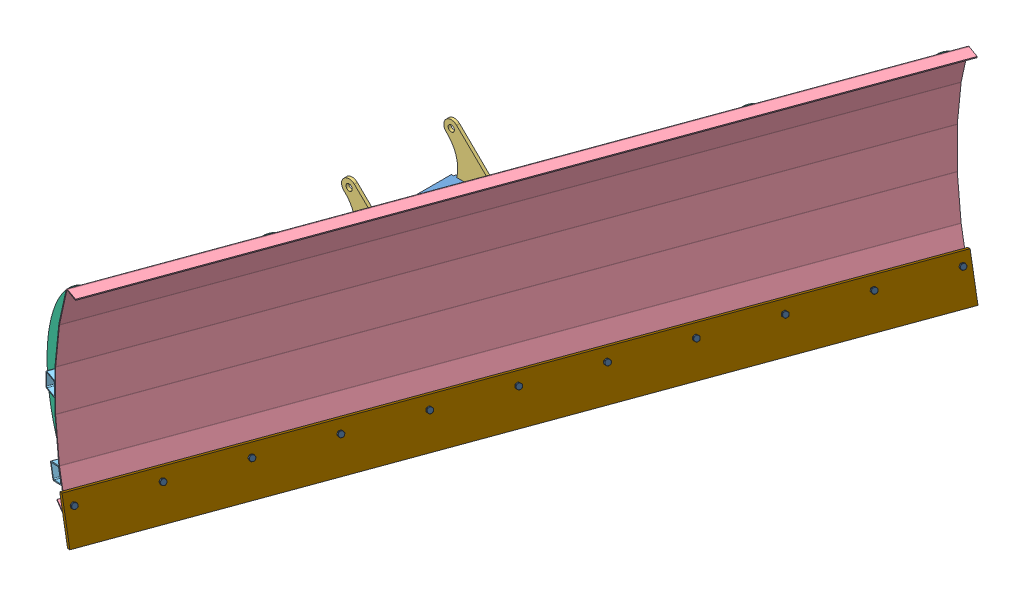
SolidWorks assembly ТП.016.11.00 - Отвал поворотный, configuration 00. Lengths in mm.
Overall size (742.58 437.97 1419.72).
58 component instances, 12 part files, 11 mates.
Components (placement in the parent):
- ТП.016.11.01.00 - Навеска поворотная-1: ТП.016.11.01.00 - Навеска поворотная [00] at origin size (254.02 180 209.34)
  - ТП.016.11.01.01.00 - Цапфа навески нижняя-1: ТП.016.11.01.01.00 - Цапфа навески нижняя [00] at origin size (200 19 209.34)
    - ТП.016.11.01.01.01 - Цапфа навески (Ст3 S-4мм)-1: ТП.016.11.01.01.01 - Цапфа навески (Ст3 S-4мм) [--] at origin size (200 4 209.34)
    - ТП.016.11.01.01.02 - Усилитель цапфы-1: ТП.016.11.01.01.02 - Усилитель цапфы [--] at (0 4 0) size (140.53 15 187.34)
  - ТП.016.11.01.02 - Кронштейн навески (Ст3 S-6мм)-1: ТП.016.11.01.02 - Кронштейн навески (Ст3 S-6мм) [--] at (-42.4802 0.2 98.6677) x (-1 0 0) z (0 0 1) size (156.54 180 6)
  - ТП.016.11.01.01.01 - Цапфа навески (Ст3 S-4мм)-1: ТП.016.11.01.01.01 - Цапфа навески (Ст3 S-4мм) [--] at (0 19.4 0) size (200 4 209.34)
  - ТП.016.11.01.02 - Кронштейн навески (Ст3 S-6мм)-2: ТП.016.11.01.02 - Кронштейн навески (Ст3 S-6мм) [--] at (-42.4802 0.2 -104.6677) x (-1 0 0) z (0 0 1) size (156.54 180 6)
- ТП.016.11.02.00 - Отвал в сборе-1: ТП.016.11.02.00 - Отвал в сборе [00] at (96.0852 49.6474 34.9722) x (0.939693 0 0.34202) z (-0.34202 0 0.939693) size (277.03 437.97 1410)
  - ТП.016.11.02.01 - Полотно отвала (Ст3 S-2мм)-1: ТП.016.11.02.01 - Полотно отвала (Ст3 S-2мм) [--] at origin size (68.17 399.04 1400)
  - ТП.016.11.02.02 - Продольная труба-1: ТП.016.11.02.02 - Продольная труба [--] at origin size (30 30 1400)
  - ТП.016.11.02.02 - Продольная труба-2: ТП.016.11.02.02 - Продольная труба [--] at (-7.8024 -145.4172 0) x (-0.951057 -0.309017 0) z (0 0 1) size (30 30 1400)
  - ТП.016.11.02.03 - Ребро жесткости отвала (Ст3 S-2мм)-1: ТП.016.11.02.03 - Ребро жесткости отвала (Ст3 S-2мм) [--] at (0 0 675) size (117.05 393.58 2)
  - ТП.016.11.02.03 - Ребро жесткости отвала (Ст3 S-2мм)-2: ТП.016.11.02.03 - Ребро жесткости отвала (Ст3 S-2мм) [--] at (0 0 373) size (117.05 393.58 2)
  - ТП.016.11.02.03 - Ребро жесткости отвала (Ст3 S-2мм)-3: ТП.016.11.02.03 - Ребро жесткости отвала (Ст3 S-2мм) [--] at (0 0 -371) size (117.05 393.58 2)
  - ТП.016.11.02.03 - Ребро жесткости отвала (Ст3 S-2мм)-4: ТП.016.11.02.03 - Ребро жесткости отвала (Ст3 S-2мм) [--] at (0 0 -673) size (117.05 393.58 2)
  - ТП.016.11.02.04.00 - Кронштейн силовой-1: ТП.016.11.02.04.00 - Кронштейн силовой [00] at (-102.2517 -49.6474 0) size (244.94 251.23 220)
    - ТП.016.11.02.04.01 - Цапфа отвала (Ст3 S-5мм)-1: ТП.016.11.02.04.01 - Цапфа отвала (Ст3 S-5мм) [--] at origin size (208.66 5 220)
    - ТП.016.11.02.04.02 - Ребро силовое (Ст3 S-5мм)-1: ТП.016.11.02.04.02 - Ребро силовое (Ст3 S-5мм) [--] at (105.2 0.2 105) size (139.74 251.23 5)
    - ТП.016.11.02.04.02 - Ребро силовое (Ст3 S-5мм)-2: ТП.016.11.02.04.02 - Ребро силовое (Ст3 S-5мм) [--] at (105.2 0.2 -110) size (139.74 251.23 5)
    - ТП.016.11.02.04.01 - Цапфа отвала (Ст3 S-5мм)-2: ТП.016.11.02.04.01 - Цапфа отвала (Ст3 S-5мм) [--] at (0 25.4 0) x (1 0 0) z (0 0 -1) size (208.66 5 220)
  - ТП.016.11.02.05 - Юбка-1: ТП.016.11.02.05 - Юбка [--] at (37.9014 -187.7385 0) x (0.309017 -0.951057 0) z (0 0 1) size (85 8 1410)
  - Болты с шестигранной головкой кт.В (ГОСТ 7798-70)-1: Болты с шестигранной головкой кт.В (ГОСТ 7798-70) [Болт М6-6gx20(S10) ГОСТ 7798-77] at (42.4178 -175.75 690) x (-0.951057 -0.309017 0) z (-0.032305 0.099423 -0.994521) size (24 10.9 10)
  - Шайбы (ГОСТ 11371-78)-1: Шайбы (ГОСТ 11371-78) [Шайба 6 ГОСТ 11371-78] at (32.1464 -179.0874 690) x (0.951057 0.309017 0) z (0.304733 -0.937871 -0.165941) size (1.6 12 12)
  - Гайка (ГОСТ ISO 4032-2014)-1: Гайка (ГОСТ ISO 4032-2014) [Гайка М6 (ГОСТ ISO 4032)] at (28.9128 -180.1381 690) x (0.080366 -0.247341 0.96559) z (0.951057 0.309017 0) size (10 11.05 5.2)
  - Гайка (ГОСТ ISO 4032-2014)-2: Гайка (ГОСТ ISO 4032-2014) [Гайка М6 (ГОСТ ISO 4032)] at (28.9128 -180.1381 552) x (0.14073 -0.433124 0.89028) z (0.951057 0.309017 0) size (10 11.05 5.2)
  - Болты с шестигранной головкой кт.В (ГОСТ 7798-70)-2: Болты с шестигранной головкой кт.В (ГОСТ 7798-70) [Болт М6-6gx20(S10) ГОСТ 7798-77] at (42.4178 -175.75 552) x (-0.951057 -0.309017 0) z (-0.095584 0.294177 -0.950959) size (24 10.9 10)
  - Шайбы (ГОСТ 11371-78)-2: Шайбы (ГОСТ 11371-78) [Шайба 6 ГОСТ 11371-78] at (32.1464 -179.0874 552) x (0.951057 0.309017 0) z (0.287378 -0.884458 -0.367626) size (1.6 12 12)
  - Гайка (ГОСТ ISO 4032-2014)-3: Гайка (ГОСТ ISO 4032-2014) [Гайка М6 (ГОСТ ISO 4032)] at (28.9128 -180.1381 414) x (0.189473 -0.583138 0.789968) z (0.951057 0.309017 0) size (10 11.05 5.2)
  - Болты с шестигранной головкой кт.В (ГОСТ 7798-70)-3: Болты с шестигранной головкой кт.В (ГОСТ 7798-70) [Болт М6-6gx20(S10) ГОСТ 7798-77] at (42.4178 -175.75 414) x (-0.951057 -0.309017 0) z (-0.148605 0.45736 -0.876777) size (24 10.9 10)
  - Шайбы (ГОСТ 11371-78)-3: Шайбы (ГОСТ 11371-78) [Шайба 6 ГОСТ 11371-78] at (32.1464 -179.0874 414) x (0.951057 0.309017 0) z (0.261214 -0.803934 -0.534282) size (1.6 12 12)
  - Гайка (ГОСТ ISO 4032-2014)-4: Гайка (ГОСТ ISO 4032-2014) [Гайка М6 (ГОСТ ISO 4032)] at (28.9128 -180.1381 276) x (0.225997 -0.695549 0.68201) z (0.951057 0.309017 0) size (10 11.05 5.2)
  - Болты с шестигранной головкой кт.В (ГОСТ 7798-70)-4: Болты с шестигранной головкой кт.В (ГОСТ 7798-70) [Болт М6-6gx20(S10) ГОСТ 7798-77] at (42.4178 -175.75 276) x (-0.951057 -0.309017 0) z (-0.189933 0.584555 -0.78881) size (24 10.9 10)
  - Шайбы (ГОСТ 11371-78)-4: Шайбы (ГОСТ 11371-78) [Шайба 6 ГОСТ 11371-78] at (32.1464 -179.0874 276) x (0.951057 0.309017 0) z (0.231523 -0.712554 -0.662318) size (1.6 12 12)
  - Гайка (ГОСТ ISO 4032-2014)-5: Гайка (ГОСТ ISO 4032-2014) [Гайка М6 (ГОСТ ISO 4032)] at (28.9128 -180.1381 138) x (0.250965 -0.77239 0.583464) z (0.951057 0.309017 0) size (10 11.05 5.2)
  - Болты с шестигранной головкой кт.В (ГОСТ 7798-70)-5: Болты с шестигранной головкой кт.В (ГОСТ 7798-70) [Болт М6-6gx20(S10) ГОСТ 7798-77] at (42.4178 -175.75 138) x (-0.951057 -0.309017 0) z (-0.219391 0.675215 -0.704239) size (24 10.9 10)
  - Шайбы (ГОСТ 11371-78)-5: Шайбы (ГОСТ 11371-78) [Шайба 6 ГОСТ 11371-78] at (32.1464 -179.0874 138) x (0.951057 0.309017 0) z (0.203614 -0.626661 -0.752222) size (1.6 12 12)
  - Гайка (ГОСТ ISO 4032-2014)-6: Гайка (ГОСТ ISO 4032-2014) [Гайка М6 (ГОСТ ISO 4032)] at (28.9128 -180.1381 0) x (0.265821 -0.818113 0.509932) z (0.951057 0.309017 0) size (10 11.05 5.2)
  - Болты с шестигранной головкой кт.В (ГОСТ 7798-70)-6: Болты с шестигранной головкой кт.В (ГОСТ 7798-70) [Болт М6-6gx20(S10) ГОСТ 7798-77] at (42.4178 -175.75 0) x (-0.951057 -0.309017 0) z (-0.237644 0.731394 -0.639209) size (24 10.9 10)
  - Шайбы (ГОСТ 11371-78)-6: Шайбы (ГОСТ 11371-78) [Шайба 6 ГОСТ 11371-78] at (32.1464 -179.0874 0) x (0.951057 0.309017 0) z (0.182427 -0.561452 -0.80715) size (1.6 12 12)
  - Гайка (ГОСТ ISO 4032-2014)-7: Гайка (ГОСТ ISO 4032-2014) [Гайка М6 (ГОСТ ISO 4032)] at (28.9128 -180.1381 -138) x (0.272004 -0.837142 0.474559) z (0.951057 0.309017 0) size (10 11.05 5.2)
  - Болты с шестигранной головкой кт.В (ГОСТ 7798-70)-7: Болты с шестигранной головкой кт.В (ГОСТ 7798-70) [Болт М6-6gx20(S10) ГОСТ 7798-77] at (42.4178 -175.75 -138) x (-0.951057 -0.309017 0) z (-0.245474 0.755491 -0.607434) size (24 10.9 10)
  - Шайбы (ГОСТ 11371-78)-7: Шайбы (ГОСТ 11371-78) [Шайба 6 ГОСТ 11371-78] at (32.1464 -179.0874 -138) x (0.951057 0.309017 0) z (0.172142 -0.529798 -0.830471) size (1.6 12 12)
  - Гайка (ГОСТ ISO 4032-2014)-8: Гайка (ГОСТ ISO 4032-2014) [Гайка М6 (ГОСТ ISO 4032)] at (28.9128 -180.1381 -276) x (0.26996 -0.830852 0.486627) z (0.951057 0.309017 0) size (10 11.05 5.2)
  - Болты с шестигранной головкой кт.В (ГОСТ 7798-70)-8: Болты с шестигранной головкой кт.В (ГОСТ 7798-70) [Болт М6-6gx20(S10) ГОСТ 7798-77] at (42.4178 -175.75 -276) x (-0.951057 -0.309017 0) z (-0.242868 0.74747 -0.618307) size (24 10.9 10)
  - Шайбы (ГОСТ 11371-78)-8: Шайбы (ГОСТ 11371-78) [Шайба 6 ГОСТ 11371-78] at (32.1464 -179.0874 -276) x (0.951057 0.309017 0) z (0.175657 -0.540616 -0.822726) size (1.6 12 12)
  - Гайка (ГОСТ ISO 4032-2014)-9: Гайка (ГОСТ ISO 4032-2014) [Гайка М6 (ГОСТ ISO 4032)] at (28.9128 -180.1381 -414) x (0.258386 -0.79523 0.548494) z (0.951057 0.309017 0) size (10 11.05 5.2)
  - Болты с шестигранной головкой кт.В (ГОСТ 7798-70)-9: Болты с шестигранной головкой кт.В (ГОСТ 7798-70) [Болт М6-6gx20(S10) ГОСТ 7798-77] at (42.4178 -175.75 -414) x (-0.951057 -0.309017 0) z (-0.228423 0.703014 -0.673493) size (24 10.9 10)
  - Шайбы (ГОСТ 11371-78)-9: Шайбы (ГОСТ 11371-78) [Шайба 6 ГОСТ 11371-78] at (32.1464 -179.0874 -414) x (0.951057 0.309017 0) z (0.193572 -0.595754 -0.779491) size (1.6 12 12)
  - Гайка (ГОСТ ISO 4032-2014)-10: Гайка (ГОСТ ISO 4032-2014) [Гайка М6 (ГОСТ ISO 4032)] at (28.9128 -180.1381 -552) x (0.234692 -0.722307 0.650532) z (0.951057 0.309017 0) size (10 11.05 5.2)
  - Болты с шестигранной головкой кт.В (ГОСТ 7798-70)-10: Болты с шестигранной головкой кт.В (ГОСТ 7798-70) [Болт М6-6gx20(S10) ГОСТ 7798-77] at (42.4178 -175.75 -552) x (-0.951057 -0.309017 0) z (-0.200053 0.6157 -0.762163) size (24 10.9 10)
  - Шайбы (ГОСТ 11371-78)-10: Шайбы (ГОСТ 11371-78) [Шайба 6 ГОСТ 11371-78] at (32.1464 -179.0874 -552) x (0.951057 0.309017 0) z (0.222677 -0.685331 -0.693352) size (1.6 12 12)
  - Гайка (ГОСТ ISO 4032-2014)-11: Гайка (ГОСТ ISO 4032-2014) [Гайка М6 (ГОСТ ISO 4032)] at (28.9128 -180.1381 -690) x (0.197744 -0.608594 0.768447) z (0.951057 0.309017 0) size (10 11.05 5.2)
  - Болты с шестигранной головкой кт.В (ГОСТ 7798-70)-11: Болты с шестигранной головкой кт.В (ГОСТ 7798-70) [Болт М6-6gx20(S10) ГОСТ 7798-77] at (42.4178 -175.75 -690) x (-0.951057 -0.309017 0) z (-0.157821 0.485724 -0.859747) size (24 10.9 10)
  - Шайбы (ГОСТ 11371-78)-11: Шайбы (ГОСТ 11371-78) [Шайба 6 ГОСТ 11371-78] at (32.1464 -179.0874 -690) x (0.951057 0.309017 0) z (0.25539 -0.786011 -0.562994) size (1.6 12 12)
- Болты с шестигранной головкой кт.В (ГОСТ 7798-70)-1: Болты с шестигранной головкой кт.В (ГОСТ 7798-70) [Болт М12-6gx50(S18) ГОСТ 7798-77] at (0 30.4 0) x (0 -1 0) z (-0.962757 0 -0.270368) size (57.5 19.9 18)
- Гайка (ГОСТ ISO 4032-2014)-1: Гайка (ГОСТ ISO 4032-2014) [Гайка М12 (ГОСТ ISO 4032)] at (0 -10.4 0) x (-0.731463 0 0.681881) z (0 1 0) size (18 20.3 10.8)
- Болты с шестигранной головкой кт.В (ГОСТ 7798-70)-2: Болты с шестигранной головкой кт.В (ГОСТ 7798-70) [Болт М10-6gx50(S16) ГОСТ 7798-77] at (-70 30.4 0) x (0 -1 0) z (0.739099 0 0.673597) size (56.4 17.6 16)
- Гайка (ГОСТ ISO 4032-2014)-2: Гайка (ГОСТ ISO 4032-2014) [Гайка М10 (ГОСТ ISO 4032)] at (-70 -9.2 0) x (0.537497 0 -0.843266) z (0 -1 0) size (16 17.77 8.4)
Mates (geometry in assembly coordinates):
- Совпадение1: coincident: plane of ТП.016.11.01.00 - Навеска поворотная-1/ТП.016.11.01.01.00 - Цапфа навески нижняя-1/ТП.016.11.01.01.01 - Цапфа навески (Ст3 S-4мм)-1 through (-70 0 0) normal (0 -1 0); plane of ТП.016.11.02.00 - Отвал в сборе-1/ТП.016.11.02.04.00 - Кронштейн силовой-1/ТП.016.11.02.04.01 - Цапфа отвала (Ст3 S-5мм)-1 through (0 0 0) normal (0 1 0)
- Концентричный1: concentric: cylinder of ТП.016.11.01.00 - Навеска поворотная-1/ТП.016.11.01.01.01 - Цапфа навески (Ст3 S-4мм)-1 through (0 23.4 0) axis (0 -1 0) radius 6.25; cylinder of ТП.016.11.02.00 - Отвал в сборе-1/ТП.016.11.02.04.00 - Кронштейн силовой-1/ТП.016.11.02.04.01 - Цапфа отвала (Ст3 S-5мм)-2 through (0 30.4 0) axis (0 -1 0) radius 6.25
- Концентричный2: concentric: cylinder of ТП.016.11.01.00 - Навеска поворотная-1/ТП.016.11.01.01.01 - Цапфа навески (Ст3 S-4мм)-1 through (-70 23.4 0) axis (0 -1 0) radius 5.1; cylinder of ТП.016.11.02.00 - Отвал в сборе-1/ТП.016.11.02.04.00 - Кронштейн силовой-1/ТП.016.11.02.04.01 - Цапфа отвала (Ст3 S-5мм)-2 through (-70 30.4 0) axis (0 -1 0) radius 5.1
- Концентричный3: concentric: cylinder of ТП.016.11.02.00 - Отвал в сборе-1/ТП.016.11.02.04.00 - Кронштейн силовой-1/ТП.016.11.02.04.01 - Цапфа отвала (Ст3 S-5мм)-1 through (0 -5 0) axis (0 1 0) radius 6.25; cylinder of Болты с шестигранной головкой кт.В (ГОСТ 7798-70)-1 through (0 1030.4 0) axis (0 1 0) radius 6
- Совпадение2: coincident: plane of ТП.016.11.02.00 - Отвал в сборе-1/ТП.016.11.02.04.00 - Кронштейн силовой-1/ТП.016.11.02.04.01 - Цапфа отвала (Ст3 S-5мм)-2 through (0 30.4 0) normal (0 1 0); plane of Болты с шестигранной головкой кт.В (ГОСТ 7798-70)-1 through (-2.6902 30.4 9.5794) normal (0 -1 0)
- Совпадение3: coincident: plane of ТП.016.11.02.00 - Отвал в сборе-1/ТП.016.11.02.04.00 - Кронштейн силовой-1/ТП.016.11.02.04.01 - Цапфа отвала (Ст3 S-5мм)-1 through (0 -5 0) normal (0 -1 0); plane of Гайка (ГОСТ ISO 4032-2014)-1 through (5.6596 -5 6.0711) normal (0 1 0)
- Концентричный4: concentric: cylinder of Болты с шестигранной головкой кт.В (ГОСТ 7798-70)-1 through (0 1030.4 0) axis (0 1 0) radius 6; cylinder of Гайка (ГОСТ ISO 4032-2014)-1 through (0 142.3402 0) axis (0 1 0) radius 4.4845
- Концентричный5: concentric: cylinder of ТП.016.11.01.00 - Навеска поворотная-1/ТП.016.11.01.01.01 - Цапфа навески (Ст3 S-4мм)-1 through (-70 23.4 0) axis (0 -1 0) radius 5.1; cylinder of Болты с шестигранной головкой кт.В (ГОСТ 7798-70)-2 through (-70 1030.4 0) axis (0 1 0) radius 5
- Совпадение4: coincident: plane of ТП.016.11.02.00 - Отвал в сборе-1/ТП.016.11.02.04.00 - Кронштейн силовой-1/ТП.016.11.02.04.01 - Цапфа отвала (Ст3 S-5мм)-2 through (0 30.4 0) normal (0 1 0); plane of Болты с шестигранной головкой кт.В (ГОСТ 7798-70)-2 through (-64.0723 30.4 -6.5041) normal (0 -1 0)
- Совпадение6: coincident: plane of ТП.016.11.02.00 - Отвал в сборе-1/ТП.016.11.02.04.00 - Кронштейн силовой-1/ТП.016.11.02.04.01 - Цапфа отвала (Ст3 S-5мм)-1 through (0 -5 0) normal (0 -1 0); plane of Гайка (ГОСТ ISO 4032-2014)-2 through (-63.8442 -5 3.9237) normal (0 1 0)
- Концентричный6: concentric: cylinder of Болты с шестигранной головкой кт.В (ГОСТ 7798-70)-2 through (-70 1030.4 0) axis (0 1 0) radius 5; cylinder of Гайка (ГОСТ ISO 4032-2014)-2 through (-70 -161.9402 0) axis (0 -1 0) radius 3.701
